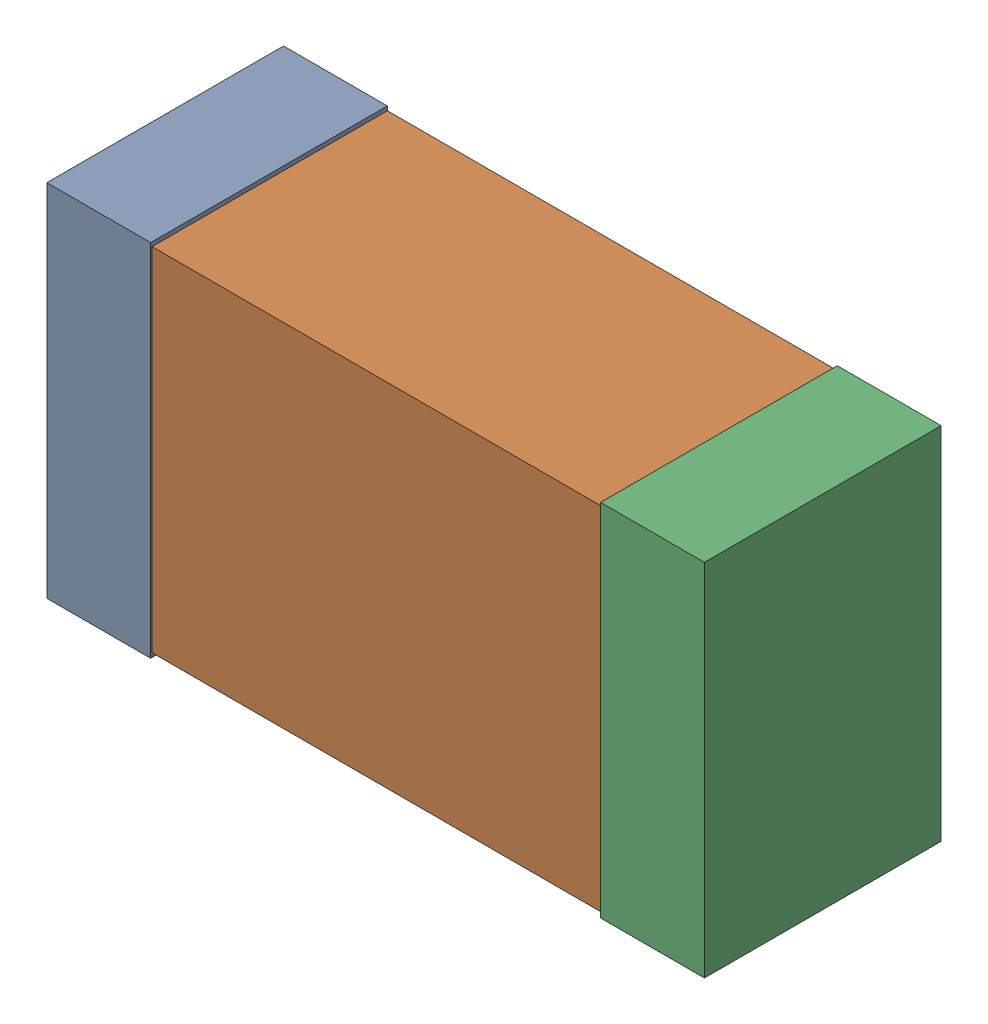
SolidWorks assembly C9_Motor_1Kanaloa_v2.0.0_Motor, configuration Default. Lengths in mm.
Overall size (2.38 1.3 0.85).
6 component instances, 2 part files, 0 mates.
Components (placement in the parent):
- 352877648-1: 352877648 [Default] at (76.681 50.292 0) size (0.38 1.3 0.85)
  - Extruded_14-1: Extruded_14 [Default] at origin size (0.38 1.3 0.85)
- 352877392-1: 352877392 [Default] at (77.681 50.292 0) size (2.2 1.27 0.85)
  - Extruded_15-1: Extruded_15 [Default] at origin size (2.2 1.27 0.85)
- 352877648-2: 352877648 [Default] at (78.681 50.292 0) size (0.38 1.3 0.85)
  - Extruded_14-1: Extruded_14 [Default] at origin size (0.38 1.3 0.85)
